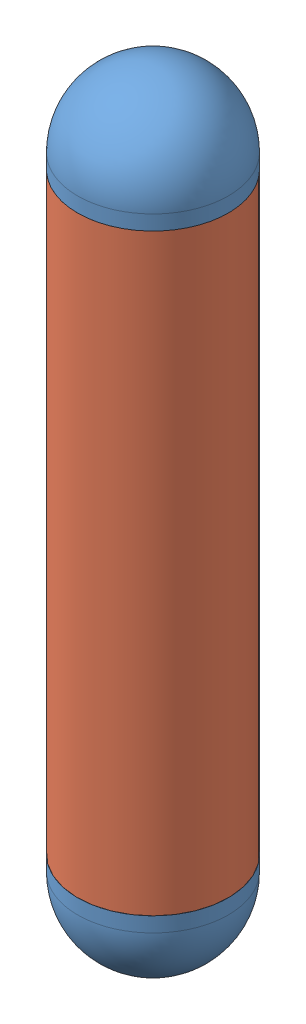
SolidWorks assembly Assem1, configuration Default. Lengths in mm.
Overall size (335.38 1304 335.38).
3 component instances, 2 part files, 4 mates.
Components (placement in the parent):
- FuelTankEndCapsV2-1: FuelTankEndCapsV2 [Default] at (191.6174 -599.1793 641.0104) size (254 177 254)
- FuelTankEndCapsV2-2: FuelTankEndCapsV2 [Default] at (191.6174 350.8207 641.0104) x (0.406927 0 0.913461) z (0.913461 0 -0.406927) size (254 177 254)
- FuelTankSideWallsV1-1: FuelTankSideWallsV1 [Default] at (191.6174 -624.1793 641.0104) x (0.960015 0 -0.279949) z (0.279949 0 0.960015) size (254 1000 254)
Mates (geometry in assembly coordinates):
- Concentric1: concentric: cylinder of FuelTankEndCapsV2-1 through (191.6174 400.8207 641.0104) axis (0 1 0) radius 124.5; cylinder of FuelTankSideWallsV1-1 through (191.6174 -624.1793 641.0104) axis (0 -1 0) radius 124.5
- Coincident1: coincident: plane of FuelTankEndCapsV2-1 through (318.6174 375.8207 641.0104) normal (0 -1 0); circle of FuelTankSideWallsV1-1
- Concentric2: concentric aligned: cylinder of FuelTankEndCapsV2-2 through (191.6174 -649.1793 641.0104) axis (0 -1 0) radius 124.5; cylinder of FuelTankSideWallsV1-1 through (191.6174 -624.1793 641.0104) axis (0 -1 0) radius 124.5
- Coincident2: coincident anti-aligned: plane of FuelTankEndCapsV2-2 through (243.2971 -624.1793 757.0199) normal (0 1 0); plane of FuelTankSideWallsV1-1 through (311.1392 -624.1793 606.1567) normal (0 -1 0)
